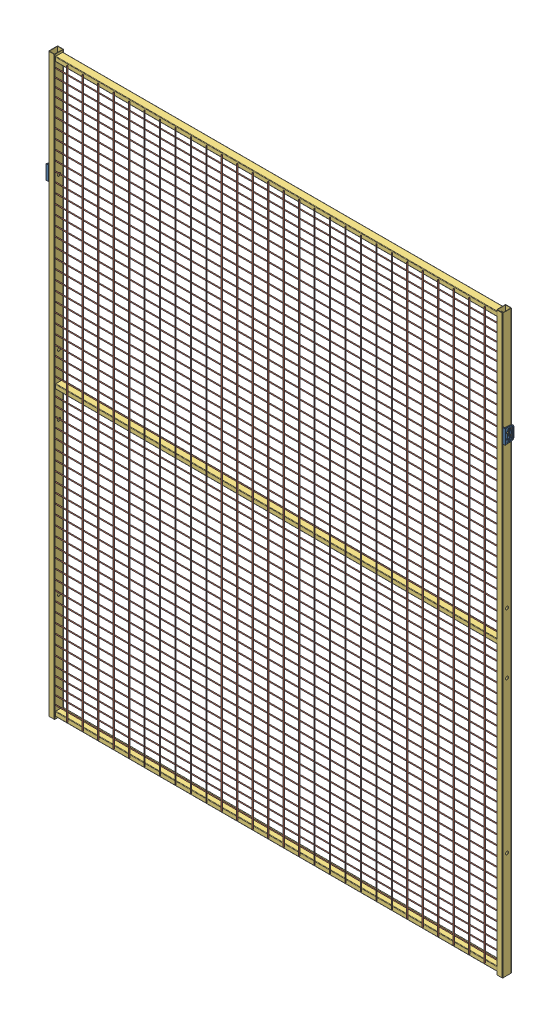
SolidWorks assembly W322-190150-Axelent, configuration Default. Lengths in mm.
Overall size (1515.63 1900 30).
4 component instances, 3 part files, 0 mates.
Components (placement in the parent):
- G2032-1: G2032 [Default] at (-749 600 0) size (9.31 48.01 29.42)
- G2032-2: G2032 [Default] at (749 600 0) x (-1 0 0) z (0 0 1) size (9.31 48.01 29.42)
- NÄT-50x30_II_N-05030-190-150-1: NÄT-50x30_II_N-05030-190-150 [Default] at (0 0 13.5) x (-1 0 0) z (0 0 -1) size (1480 1876 4.75)
- RAM-30_RAM-190-150-1: RAM-30_RAM-190-150 [Default] at origin size (1498 1900 30)
